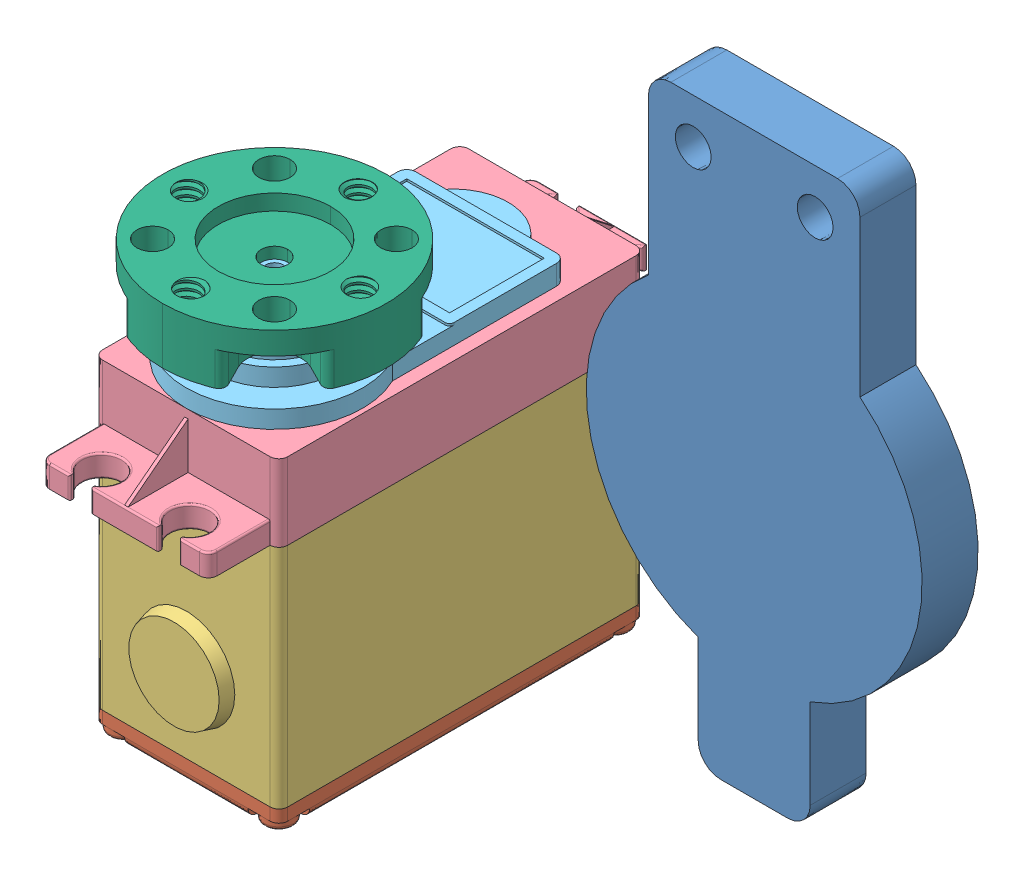
SolidWorks assembly Assem1, configuration Default. Lengths in mm.
Overall size (75.92 76.1 55.5).
7 component instances, 6 part files, 2 mates.
Components (placement in the parent):
- Cap-1: Cap [Default] at (9.8366 29.3502 25.1268) size (38.1 65.66 6.35)
- 11886-1: 11886 [Default] at (-36.5611 -7.4506 30.0276) size (21 45.43 55.5)
  - 11886_bottom-1: 11886_bottom [Default] at (2.2223 -4.2785 0.9275) size (21 2.43 41.5)
  - 11886_middle-1: 11886_middle [Default] at (2.2223 -1.8785 0.9275) size (21 25.7 42.9)
  - 11886_upper-1: 11886_upper [Default] at (6.1473 23.8215 -5.3225) size (21 8.72 55.5)
  - 11886_top-1: 11886_top [Default] at (2.2223 32.5215 0.7275) size (20 8.6 36.5)
- 525130.step-1: 525130.step [Default] at (-34.3388 30.3689 41.705) size (25.39 6.35 25.39)
Mates (geometry in assembly coordinates):
- Concentric1: concentric aligned: circle of 11886-1/11886_top-1; circle of 525130.step-1
- Coincident2: coincident anti-aligned: plane of 11886-1/11886_top-1 through (-40.7502 33.6709 41.705) normal (0 1 0); plane of 525130.step-1 through (-34.3388 33.6709 41.705) normal (0 -1 0)
